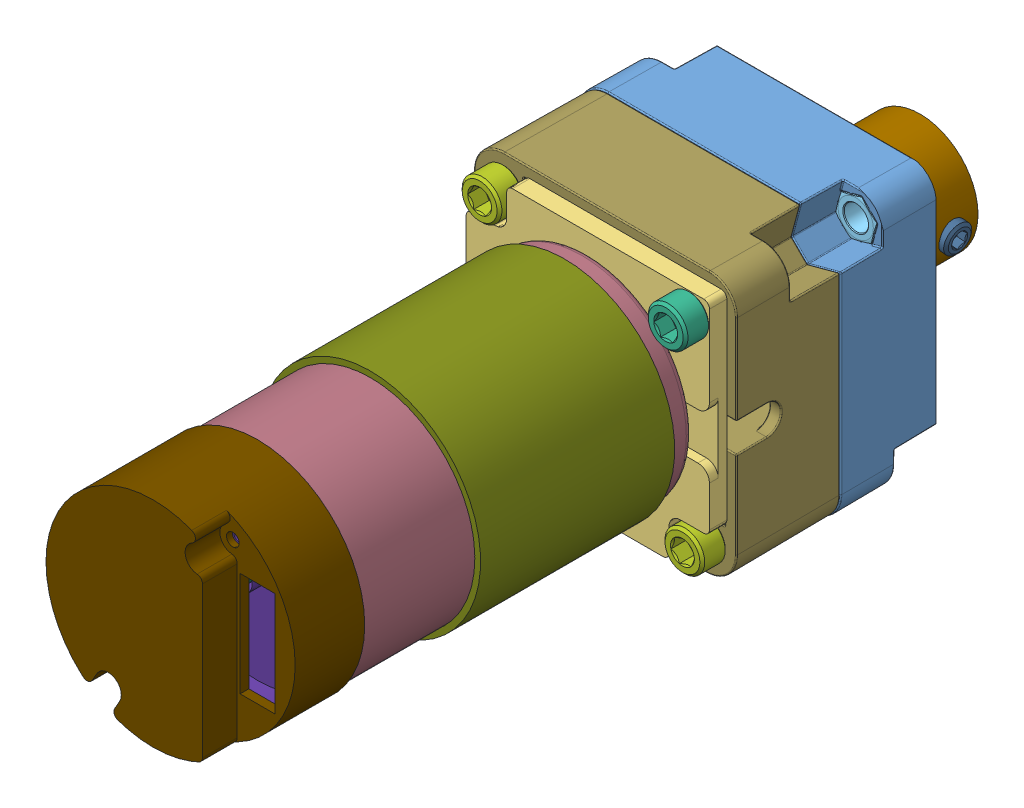
SolidWorks assembly VersaPlanetary_Lite_0_Stage_1_2_Hex_Universal_Female_Output (1), configuration Default. Lengths in mm.
Overall size (52.33 52.33 132.34).
46 component instances, 25 part files, 0 mates.
Components (placement in the parent):
- VersaPlanetary Output Blocks_VP Lite Output Block-1: VersaPlanetary Output Blocks_VP Lite Output Block [Default] at origin size (52.33 52.33 18.13)
  - 217-5823-100 Rev1-1: 217-5823-100 Rev1 [Default] at (0 0 6.9329) size (52.33 52.33 18.13)
    - 217-5823-001 Rev7-1: 217-5823-001 Rev7 [Default] at origin size (45.29 45.29 18.13)
    - 217-2742-001 Rev4-1: 217-2742-001 Rev4 [Default] at (0 0 -22.225) x (0 0 1) z (-0.999905 0.013777 0) size (7 28 28)
    - 217-2742-001 Rev4-2: 217-2742-001 Rev4 [Default] at (0 0 -13.9329) x (0 0 1) z (-0.491658 -0.870788 0) size (7 28 28)
    - 217-5823-007 Rev2-1: 217-5823-007 Rev2 [Default] at (-11.3137 11.3137 -14.225) x (0 1 0) z (1 0 0) size (3.5 6.32 3.5)
    - 217-5823-008 Rev3-1: 217-5823-008 Rev3 [Default] at (0 0 -15.225) x (0.707107 0.707107 0) z (0 0 1) size (37 37 1)
    - 217-5823-009 Rev1-1: 217-5823-009 Rev1 [Default] at (-17.4998 17.4998 -12.675) x (0.258819 -0.965926 0) z (-0.965926 -0.258819 0) size (7.33 7.23 6.35)
    - 217-5823-009 Rev1-2: 217-5823-009 Rev1 [Default] at (-17.9605 -17.9605 -16.95) x (0.707107 -0.707107 0) z (-0.707107 -0.707107 0) size (7.33 7.23 6.35)
    - 217-5823-009 Rev1-3: 217-5823-009 Rev1 [Default] at (17.9605 17.9605 -16.95) x (-0.258819 -0.965926 0) z (-0.965926 0.258819 0) size (7.33 7.23 6.35)
    - 217-5823-009 Rev1-4: 217-5823-009 Rev1 [Default] at (17.4998 -17.4998 -12.675) x (0.258819 -0.965926 0) z (-0.965926 -0.258819 0) size (7.33 7.23 6.35)
    - 217-5823-007 Rev2-2: 217-5823-007 Rev2 [Default] at (11.3137 11.3137 -14.225) x (1 0 0) z (0 -1 0) size (3.5 6.32 3.5)
    - 217-5823-007 Rev2-3: 217-5823-007 Rev2 [Default] at (11.3137 -11.3137 -14.225) x (0 -1 0) z (-1 0 0) size (3.5 6.32 3.5)
    - 217-5823-007 Rev2-4: 217-5823-007 Rev2 [Default] at (-11.3137 -11.3137 -14.225) x (-1 0 0) z (0 1 0) size (3.5 6.32 3.5)
    - 217-2625-017 Rev1_9714K61-1: 217-2625-017 Rev1_9714K61 [Default] at (-0.2889 -0.1863 -14.225) x (0.928856 0.370441 0) z (0.370441 -0.928856 0) size (28.51 4.98 30.18)
- VersaPlanetary Output Shafts_0.500 Hex-1: VersaPlanetary Output Shafts_0.500 Hex [Default] x (-1 0 0) z (0 0 -1) size (22.58 22.1 42.62)
  - 217-5839-000 Rev1_500 Hex-1: 217-5839-000 Rev1_500 Hex [Default] at (0 0 7.6524) x (-1 0 0) z (0 0 1) size (22.58 22.1 42.62)
    - 217-5839-001 Rev6-1: 217-5839-001 Rev6 [Default] at origin size (18 18 32.62)
    - 217-5839-005 Rev1_91251A148-1: 217-5839-005 Rev1_91251A148 [Default] at (0 0 1.5524) x (-0.465417 -0.885092 0) z (0 0 -1) size (5.74 5.74 16.39)
    - 217-5839-006 Rev4-1: 217-5839-006 Rev4 [Default] at (0 0 18.2524) x (0.993768 0.111469 0) z (0 0 1) size (20 20 18)
    - 217-4649-007 Rev1_94105A824-1: 217-4649-007 Rev1_94105A824 [Default] at (9.1095 1.0218 24.0024) x (0.016297 -0.145289 -0.989255) z (0.993768 0.111469 0) size (4.83 4.83 4.9)
- 217-2625-018 Rev1_98541A410-1: 217-2625-018 Rev1_98541A410 [Default] at (0 0 0.5) x (0 0 1) z (-1 0 0) size (1 19.6 17.4)
- VersaPlanetary Input Blocks_VP LIte Input Block-1: VersaPlanetary Input Blocks_VP LIte Input Block [Default] at (0 0 0.4329) size (45.6 45.6 18.01)
  - 217-5823-200 Rev1-1: 217-5823-200 Rev1 [Default] at (0 0 10.5) size (45.6 45.6 18.01)
    - 217-5823-002 Rev7-1: 217-5823-002 Rev7 [Default] at origin size (45.31 45.31 18.01)
    - 217-5823-009 Rev1-1: 217-5823-009 Rev1 [Default] at (17.9605 17.9605 1.325) x (0.707107 -0.707107 0) z (-0.707107 -0.707107 0) size (7.33 7.23 6.35)
    - 217-5823-009 Rev1-2: 217-5823-009 Rev1 [Default] at (-17.9605 -17.9605 1.325) x (0.707107 -0.707107 0) z (-0.707107 -0.707107 0) size (7.33 7.23 6.35)
- VersaPlanetary All Non-CIM Motors_NeveRest Motor-1: VersaPlanetary All Non-CIM Motors_NeveRest Motor [Default] at (0 0 18.4329) size (42 42 92.9)
  - am-3104-1: am-3104 [Default] at (0 0 31.5) x (0 1 0) z (0 0 -1) size (38 37.8 83.6)
    - am-3104-001-1: am-3104-001 [Default] at origin size (36 36 61)
    - am-3104-002-1: am-3104-002 [Default] at (0 0 29.9) size (12 12 4)
    - am-3104-003-1: am-3104-003 [Default] at (0 0 -2.4) size (3.18 3.18 79)
    - am-3104-004-1: am-3104-004 [Default] at (0 0 7.75) size (38 37.8 33.5)
    - am-3104-005-1: am-3104-005 [Default] at (0 0 -32) size (35 35 11)
    - am-3104-006-1: am-3104-006 [Default] at (0 0 -37.5) size (37 37 18)
  - 217-2625-012 Rev1-1: 217-2625-012 Rev1 [Default] at (0 0 -9.5142) size (8.01 7.94 7.5)
  - 217-4649-001 Rev1-1: 217-4649-001 Rev1 [Default] at (0 0 -10.5) x (-0.037394 -0.999301 0) z (0 0 -1) size (18 18 13)
  - 217-4649-007 Rev1_94105A824-1: 217-4649-007 Rev1_94105A824 [Default] at (-6.7787 0.2537 -5.025) x (0.037394 0.999301 0) z (-0.999301 0.037394 0) size (4.83 4.83 4.9)
  - 217-2822-001 Rev4-1: 217-2822-001 Rev4 [Default] at (0 0 1.5) size (42 42 4.8)
  - 217-4649-005 Rev1_SSA0003-008BA-1: 217-4649-005 Rev1_SSA0003-008BA [Default] at (0 -12.5 0) x (0.07598 0.997109 0) z (-0.997109 0.07598 0) size (5.5 11 5.5)
  - 217-4649-005 Rev1_SSA0003-008BA-2: 217-4649-005 Rev1_SSA0003-008BA [Default] at (0 12.5 0) x (0.246835 -0.969058 0) z (0.969058 0.246835 0) size (5.5 11 5.5)
  - 217-4649-006 Rev1_SSA0004-008BA-1: 217-4649-006 Rev1_SSA0004-008BA [Default] at (0 12.5 0) x (1 0 0) z (0 1 0) size (7 14 7)
- #8-32 SHCS, Grade 8 Steel Rev2_SSA0832-0500ZB-1: #8-32 SHCS, Grade 8 Steel Rev2_SSA0832-0500ZB [Default] at (-17.9605 -17.9605 9.0829) size (6.86 6.86 17.07)
- #8-32 SHCS, Grade 8 Steel Rev2_SSA0832-0500ZB-2: #8-32 SHCS, Grade 8 Steel Rev2_SSA0832-0500ZB [Default] at (17.9605 17.9605 9.0829) x (-0.997343 -0.072854 0) z (0 0 1) size (6.86 6.86 17.07)
- #8-32 SHCS, Grade 8 Steel Rev2_SSA0832-1125ZB-1: #8-32 SHCS, Grade 8 Steel Rev2_SSA0832-1125ZB [Default] at (-17.4998 17.4998 -10.1421) size (6.86 6.86 32.95)
- #8-32 SHCS, Grade 8 Steel Rev2_SSA0832-1125ZB-2: #8-32 SHCS, Grade 8 Steel Rev2_SSA0832-1125ZB [Default] at (17.4998 -17.4998 -10.1421) x (-0.266391 -0.963865 0) z (0 0 1) size (6.86 6.86 32.95)
